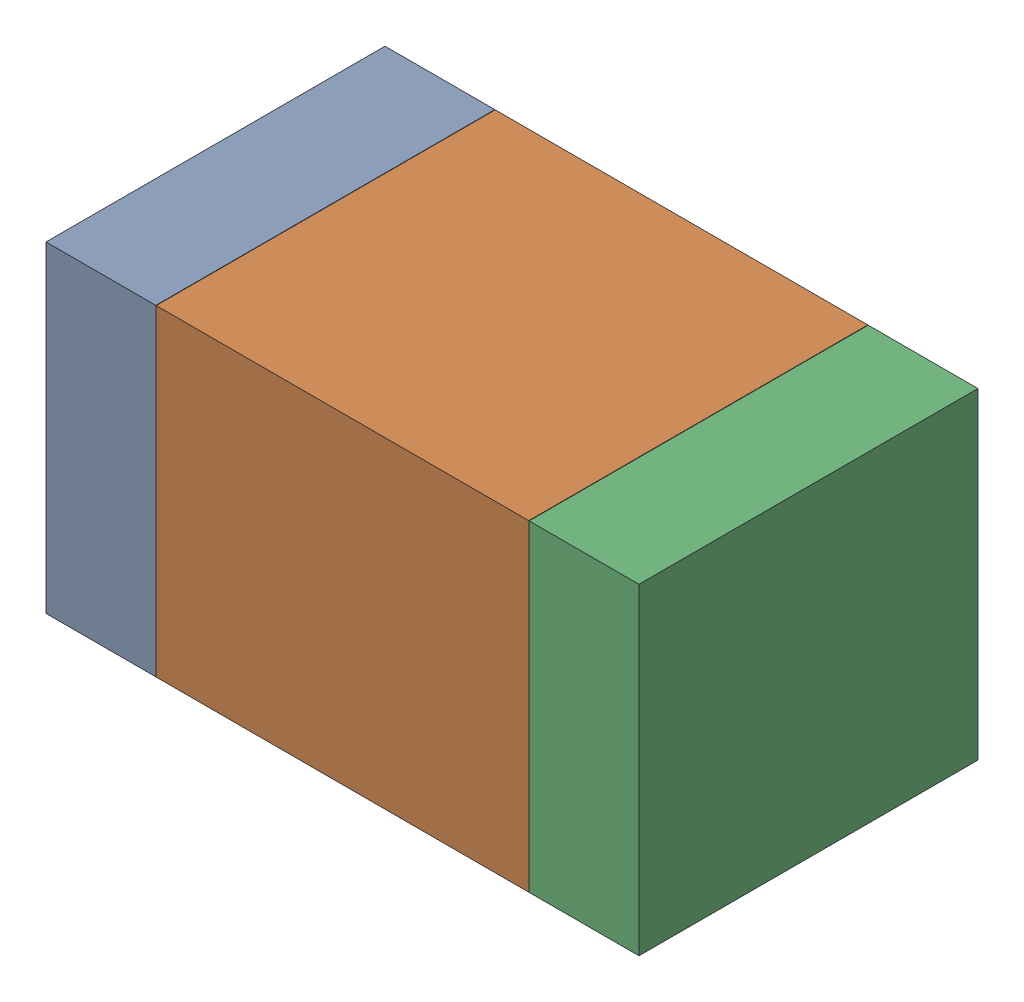
SolidWorks assembly C7, configuration Default. Lengths in mm.
Overall size (1.75 0.95 1).
6 component instances, 2 part files, 0 mates.
Components (placement in the parent):
- 6575498272-1: 6575498272 [Default] at (33.5775 18.288 0) size (0.32 0.95 1)
  - Extruded_8-1: Extruded_8 [Default] at origin size (0.32 0.95 1)
- 6575498112-1: 6575498112 [Default] at (34.29 18.288 0) size (1.1 0.95 1)
  - Extruded_9-1: Extruded_9 [Default] at origin size (1.1 0.95 1)
- 6575498272-2: 6575498272 [Default] at (35.0025 18.288 0) size (0.32 0.95 1)
  - Extruded_8-1: Extruded_8 [Default] at origin size (0.32 0.95 1)
